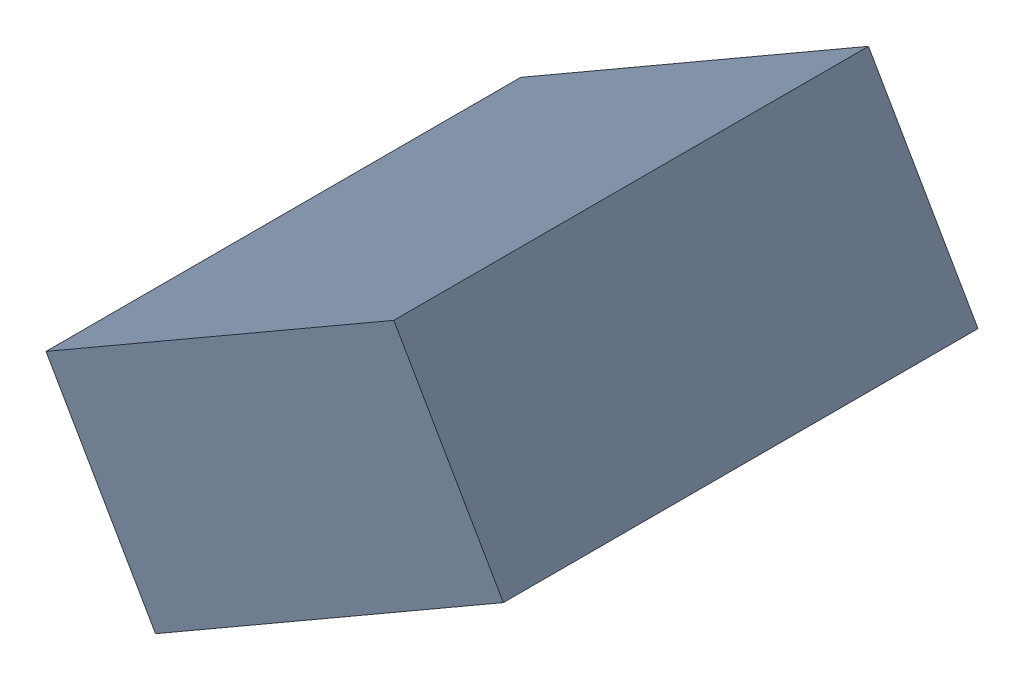
SolidWorks assembly C25_TDA5, configuration Standard. Lengths in mm.
Overall size (1.25 1.07 1.3).
2 component instances, 1 part files, 0 mates.
Components (placement in the parent):
- 885542920-1: 885542920 [Standard] at (-36.0907 -21.4648 0) size (1.25 1.07 1.3)
  - Extruded_24-1: Extruded_24 [Standard] at origin size (1.25 1.07 1.3)
